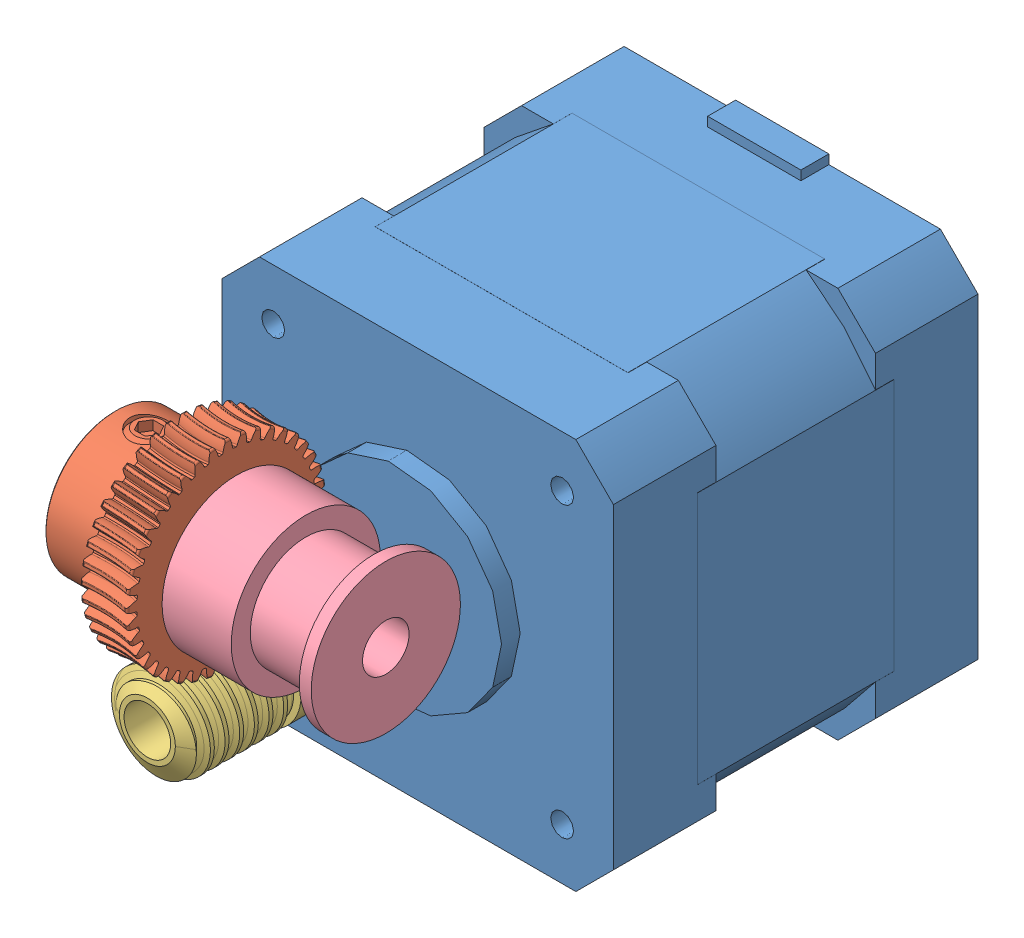
SolidWorks assembly Z-axis gear box, configuration Default. Lengths in mm.
Overall size (42.02 46.72 73.33).
8 component instances, 6 part files, 14 mates.
Components (placement in the parent):
- STEPPER-1: STEPPER [Default] at origin size (42.02 53.01 63.12)
- 57545K738_Metal Worm Gear-1: 57545K738_Metal Worm Gear [57545K738] at (0 14.5 62.116) x (0 -0.999708 0.024157) z (1 0 0) size (21.47 21.47 12.02)
- Brass worm gear-1: Brass worm gear [57545K611] at (0 0 62.116) size (10.21 10.22 20)
- Drive spool-1: Drive spool [Default] at (-17.5 14.5 62.116) x (0 -0.42995 0.902853) z (0 -0.902853 -0.42995) size (22 25.5 22) (hidden)
- F695-2RS - flange bearing-1: F695-2RS - flange bearing [4668K226] at (-45.5 14.5 62.116) x (0 0.125565 -0.992085) z (1 0 0) size (15 15 4) (hidden)
- F695-2RS - flange bearing-2: F695-2RS - flange bearing [4668K226] at (8.6952 14.5 62.116) x (0 -0.668168 -0.74401) z (-1 0 0) size (15 15 4) (hidden)
- F695-2RS - flange bearing-3: F695-2RS - flange bearing [4668K226] at (-30.3095 14.5 62.116) x (0 0.205131 0.978734) z (1 0 0) size (15 15 4) (hidden)
- gt2 drive pulley-1: gt2 drive pulley [Default] at (3.5834 14.5 62.116) x (0 0.60747 -0.794343) z (0 -0.794343 -0.60747) size (16 16 16)
Mates (geometry in assembly coordinates):
- Concentric1: concentric anti-aligned: cylinder of Brass worm gear-1 through (0 0 56.624) axis (0 0 -1) radius 5; cylinder of STEPPER-1 through (0 0 41.116) axis (0 0 1) radius 2.5
- Coincident1: coincident anti-aligned: plane of Brass worm gear-1 through (-5.1146 -3.9328 48.116) normal (0 0 -1); plane of STEPPER-1 through (0 2.1476 48.116) normal (0 0 1)
- Coincident2: coordinate: point of STEPPER-1
- Concentric2: concentric anti-aligned: cylinder of 57545K738_Metal Worm Gear-1 through (-2.15 14.5 62.116) axis (-1 0 0) radius 7.5; cylinder of Drive spool-1 through (-17.5 14.5 62.116) axis (1 0 0) radius 11
- Parallel1: parallel aligned: plane of STEPPER-1 through (-21 16.9706 30.116) normal (-1 0 0); plane of 57545K738_Metal Worm Gear-1 through (-9.5 14.5 62.116) normal (-1 0 0)
- Width1: width anti-aligned: plane of STEPPER-1 through (-21 16.9706 30.116) normal (-1 0 0); plane of 57545K738_Metal Worm Gear-1 through (21 -16.9706 30.116) normal (1 0 0); plane of STEPPER-1 through (2.5 14.5 62.116) normal (1 0 0); plane of 57545K738_Metal Worm Gear-1 through (-2.5 14.5 62.116) normal (-1 0 0)
- Distance1: distance = 14.5 mm: line of 57545K738_Metal Worm Gear-1 through (-2.675 14.5 62.116) axis (-1 0 0); line of Brass worm gear-1 through (0 0 67.584) axis (0 0 -1)
- Distance2: distance = 6 mm: plane of Brass worm gear-1 through (-5.1146 -3.9328 68.116) normal (0 0 1); line of 57545K738_Metal Worm Gear-1 through (1.6668 14.5 62.116) axis (-1 0 0)
- Concentric3: concentric anti-aligned: cylinder of Drive spool-1 through (-17.5 14.5 62.116) axis (1 0 0) radius 9; cylinder of F695-2RS - flange bearing-2 through (6.6952 14.5 62.116) axis (-1 0 0) radius 6.5
- Concentric4: concentric anti-aligned: cylinder of 57545K738_Metal Worm Gear-1 through (-2.15 14.5 62.116) axis (-1 0 0) radius 7.5; cylinder of F695-2RS - flange bearing-1 through (-43.5 14.5 62.116) axis (1 0 0) radius 6.5
- Distance5: distance = 8 mm anti-aligned: plane of 57545K738_Metal Worm Gear-1 through (-9.5 14.5 62.116) normal (-1 0 0); plane of Drive spool-1 through (-17.5 9.7706 72.0474) normal (1 0 0)
- Distance3: distance = 0.5 mm anti-aligned: plane of Drive spool-1 through (-43 13.4251 64.3731) normal (-1 0 0); plane of F695-2RS - flange bearing-1 through (-43.5 17.358 62.4777) normal (1 0 0)
- Concentric5: concentric aligned: cylinder of Drive spool-1 through (-17.5 14.5 62.116) axis (1 0 0) radius 11; cylinder of F695-2RS - flange bearing-3 through (-28.3095 14.5 62.116) axis (1 0 0) radius 6.5
- Concentric6: concentric aligned: cylinder of 57545K738_Metal Worm Gear-1 through (-2.15 14.5 62.116) axis (-1 0 0) radius 7.5; cylinder of gt2 drive pulley-1 through (3.5834 14.5 62.116) axis (-1 0 0) radius 5.96
